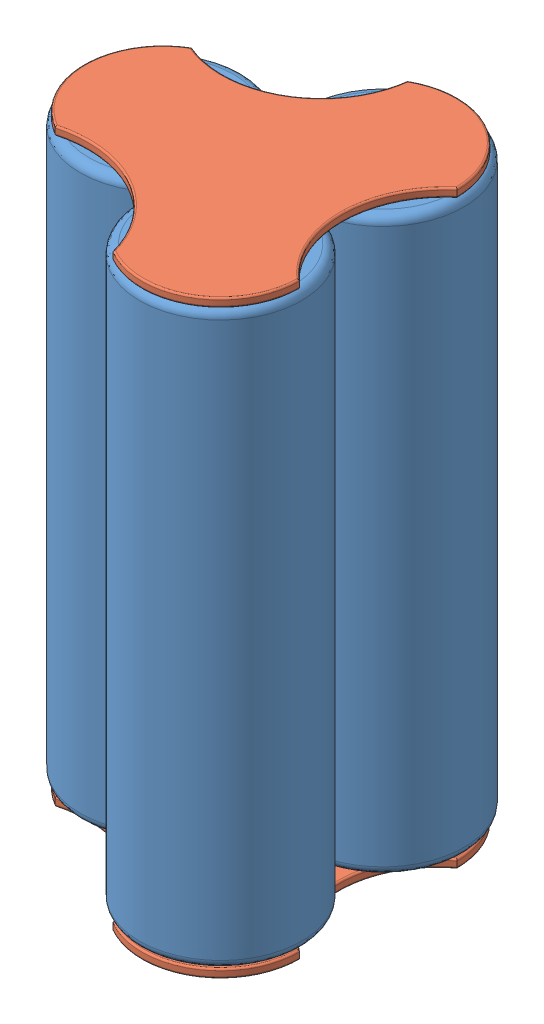
SolidWorks assembly CellTriple, configuration Default. Lengths in mm.
Overall size (47.98 67.32 47.1).
5 component instances, 2 part files, 10 mates.
Components (placement in the parent):
- Battery Cell-1: Battery Cell [Default] at (23.6992 39.4879 47.4633) size (18.5 65.8 18.5)
- Battery Cell-2: Battery Cell [Default] at (7.6777 39.4879 56.7133) size (18.5 65.8 18.5)
- Battery Cell-3: Battery Cell [Default] at (23.6992 39.4879 65.9633) size (18.5 65.8 18.5)
- Battery Conn-1: Battery Conn [Default] at (8.113 72.6379 56.9595) x (0.865901 0 0.500215) z (-0.500215 0 0.865901) size (36 1.02 33.6)
- Battery Conn-2: Battery Conn [Default] at (23.6992 6.3379 65.9633) x (-0.865901 0 -0.500215) z (-0.500215 0 0.865901) size (36 1.02 33.6)
Mates (geometry in assembly coordinates):
- Coincident1: coincident aligned: plane of Battery Cell-1 through (23.6992 72.1379 47.4633) normal (0 1 0); plane of Battery Cell-2 through (7.6777 72.1379 56.7133) normal (0 1 0)
- Coincident2: coincident aligned: plane of Battery Cell-1 through (23.6992 72.1379 47.4633) normal (0 1 0); plane of Battery Cell-3 through (23.6992 72.1379 65.9633) normal (0 1 0)
- Tangent1: tangent anti-aligned: cylinder of Battery Cell-1 through (23.6992 72.1379 47.4633) axis (0 -1 0) radius 9.25; cylinder of Battery Cell-3 through (23.6992 72.1379 65.9633) axis (0 -1 0) radius 9.25
- Tangent2: tangent anti-aligned: cylinder of Battery Cell-1 through (23.6992 72.1379 47.4633) axis (0 -1 0) radius 9.25; cylinder of Battery Cell-2 through (7.6777 72.1379 56.7133) axis (0 -1 0) radius 9.25
- Tangent3: tangent anti-aligned: cylinder of Battery Cell-2 through (7.6777 72.1379 56.7133) axis (0 -1 0) radius 9.25; cylinder of Battery Cell-3 through (23.6992 72.1379 65.9633) axis (0 -1 0) radius 9.25
- Parallel1: parallel aligned: plane of Battery Cell-2 through (7.6777 39.4879 56.7133) normal (0 0 1); plane of assembly through (0 0 0) normal (0 0 1)
- Parallel4: parallel aligned: plane of Battery Cell-3 through (23.6992 39.4879 65.9633) normal (0 0 1); plane of assembly through (0 0 0) normal (0 0 1)
- Tangent4: tangent anti-aligned: plane of Battery Cell-1 through (23.6992 39.4879 47.4633) normal (0 0 1); cylinder of Battery Cell-2 through (7.6777 72.1379 56.7133) axis (0 -1 0) radius 9.25
- Coincident7: coincident anti-aligned: plane of Battery Cell-3 through (23.6992 72.1379 65.9633) normal (0 1 0); plane of Battery Conn-1 through (32.0675 72.1379 52.4654) normal (0 -1 0)
- Concentric9: concentric aligned: cylinder of Battery Cell-3 through (23.6992 72.1379 65.9633) axis (0 -1 0) radius 9.25; cylinder of Battery Conn-1 through (23.6992 73.1379 65.9633) axis (0 -1 0) radius 9
